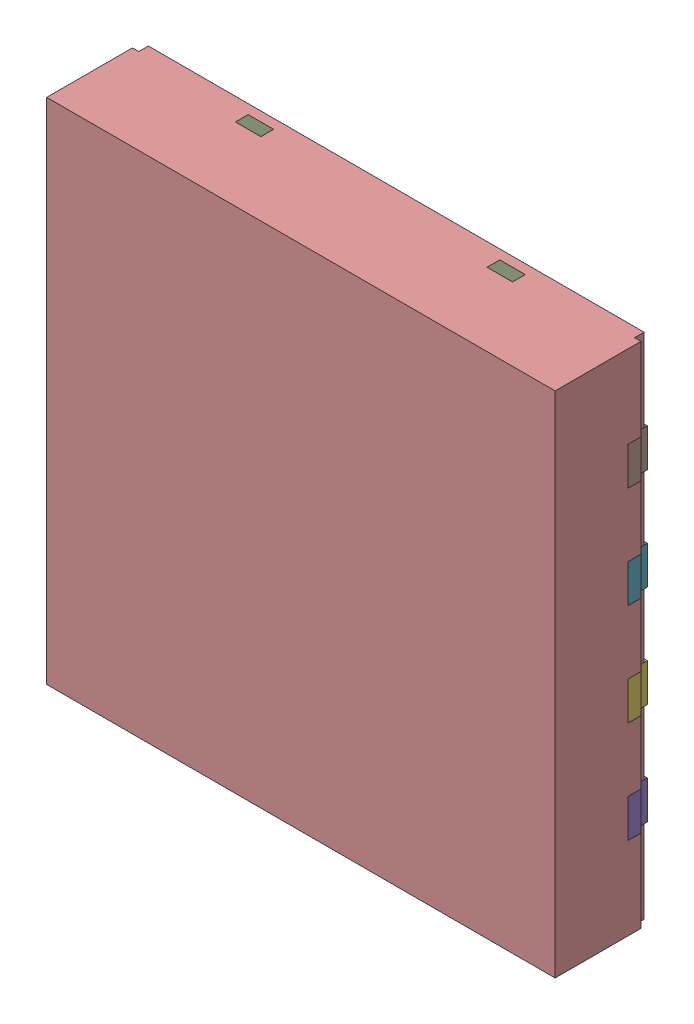
SolidWorks assembly IC7, configuration По умолчанию. Lengths in mm.
Overall size (4 4 0.78).
12 component instances, 10 part files, 0 mates.
Components (placement in the parent):
- NGU0008C_ASM-1: NGU0008C_ASM [По умолчанию] at origin size (4 4 0.78)
  - FRAME-NGU0008C_AF0-1: FRAME-NGU0008C_AF0 [По умолчанию] x (1 0 0) z (0 -1 0) size (4 0.2 4)
    - FRAME-NGU0008C_AF0-Part-1-1: FRAME-NGU0008C_AF0-Part-1 [По умолчанию] at origin size (0.4 0.2 0.3)
    - FRAME-NGU0008C_AF0-Part-2-1: FRAME-NGU0008C_AF0-Part-2 [По умолчанию] at origin size (0.4 0.2 0.3)
    - FRAME-NGU0008C_AF0-Part-3-1: FRAME-NGU0008C_AF0-Part-3 [По умолчанию] at origin size (0.4 0.2 0.3)
    - FRAME-NGU0008C_AF0-Part-4-1: FRAME-NGU0008C_AF0-Part-4 [По умолчанию] at origin size (0.4 0.2 0.3)
    - FRAME-NGU0008C_AF0-Part-5-1: FRAME-NGU0008C_AF0-Part-5 [По умолчанию] at origin size (0.4 0.2 0.3)
    - FRAME-NGU0008C_AF0-Part-6-1: FRAME-NGU0008C_AF0-Part-6 [По умолчанию] at origin size (0.4 0.2 0.3)
    - FRAME-NGU0008C_AF0-Part-7-1: FRAME-NGU0008C_AF0-Part-7 [По умолчанию] at origin size (0.4 0.2 0.3)
    - FRAME-NGU0008C_AF0-Part-8-1: FRAME-NGU0008C_AF0-Part-8 [По умолчанию] at origin size (0.4 0.2 0.3)
    - FRAME-NGU0008C_AF0-Part-9-1: FRAME-NGU0008C_AF0-Part-9 [По умолчанию] at origin size (2.18 0.2 4)
  - NGU0008C_ASM-Part-1-1: NGU0008C_ASM-Part-1 [По умолчанию] at (0 0 0.025) x (1 0 0) z (0 -1 0) size (4 0.75 4)
